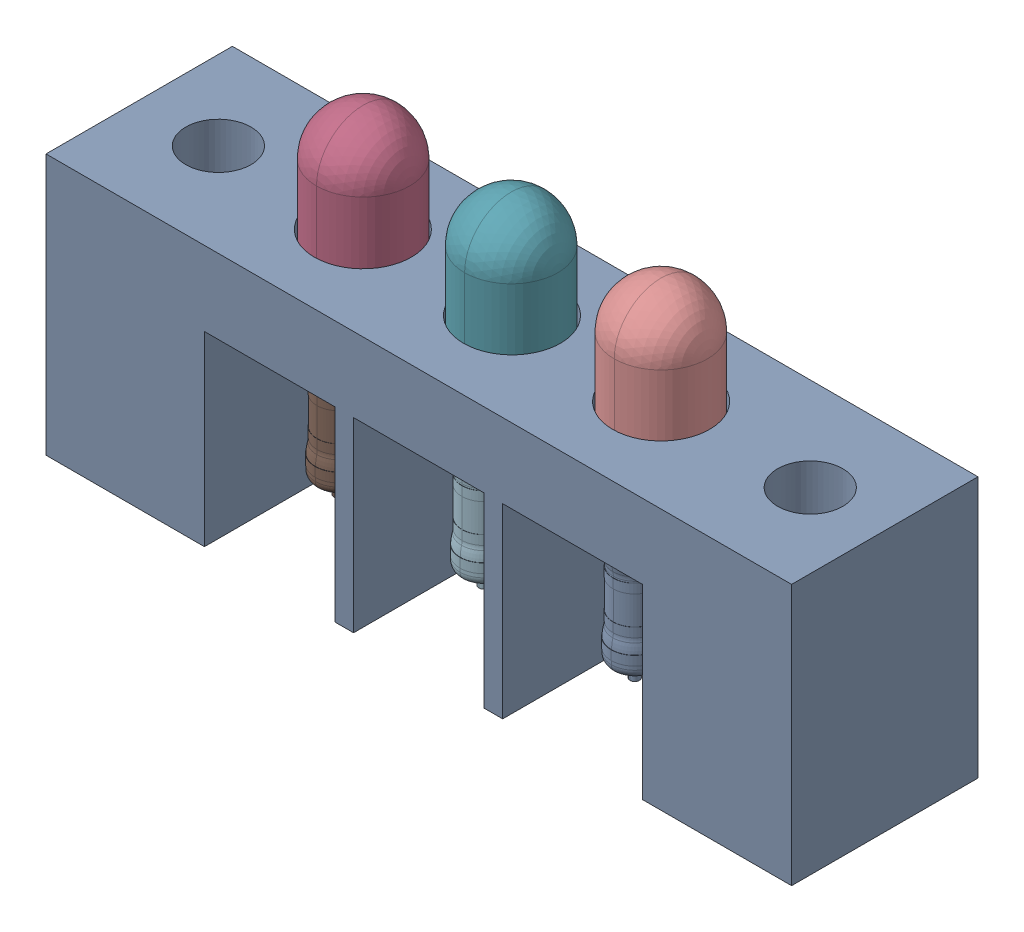
SolidWorks assembly R7_GS_112A_DIODE_PANEL, configuration Domyślna. Lengths in mm.
Overall size (40 19.75 10).
7 component instances, 3 part files, 0 mates.
Components (placement in the parent):
- R7_GS_112A1_DIODE_PANEL-1: R7_GS_112A1_DIODE_PANEL [Domyślna] at (-0.3013 3.3825 2.2765) size (40 14 10)
- R7_GS_112A2_DIODE-5: R7_GS_112A2_DIODE [Domyślna] at (-9.3005 4.3373 4.647) x (1 0 0) z (0 1 0) size (5.5 6 15.8)
- R7_GS_112A2_DIODE-6: R7_GS_112A2_DIODE [Domyślna] at (-1.3323 4.3031 4.6707) x (1 0 0) z (0 1 0) size (5.5 6 15.8)
- R7_GS_112A2_DIODE-7: R7_GS_112A2_DIODE [Domyślna] at (6.6848 4.3027 4.6595) x (1 0 0) z (0 1 0) size (5.5 6 15.8)
- R7_GS_112A3_RESISTOR-2: R7_GS_112A3_RESISTOR [Domyślna] at (-10.0216 -1.6581 4.6131) x (0 -1 0) z (0 0 1) size (7.98 2.52 2.52)
- R7_GS_112A3_RESISTOR-3: R7_GS_112A3_RESISTOR [Domyślna] at (-2.1109 -1.8475 4.7577) x (0 -1 0) z (0 0 1) size (7.98 2.52 2.52)
- R7_GS_112A3_RESISTOR-4: R7_GS_112A3_RESISTOR [Domyślna] at (5.9654 -2.1257 4.7163) x (0 -1 0) z (0 0 1) size (7.98 2.52 2.52)
